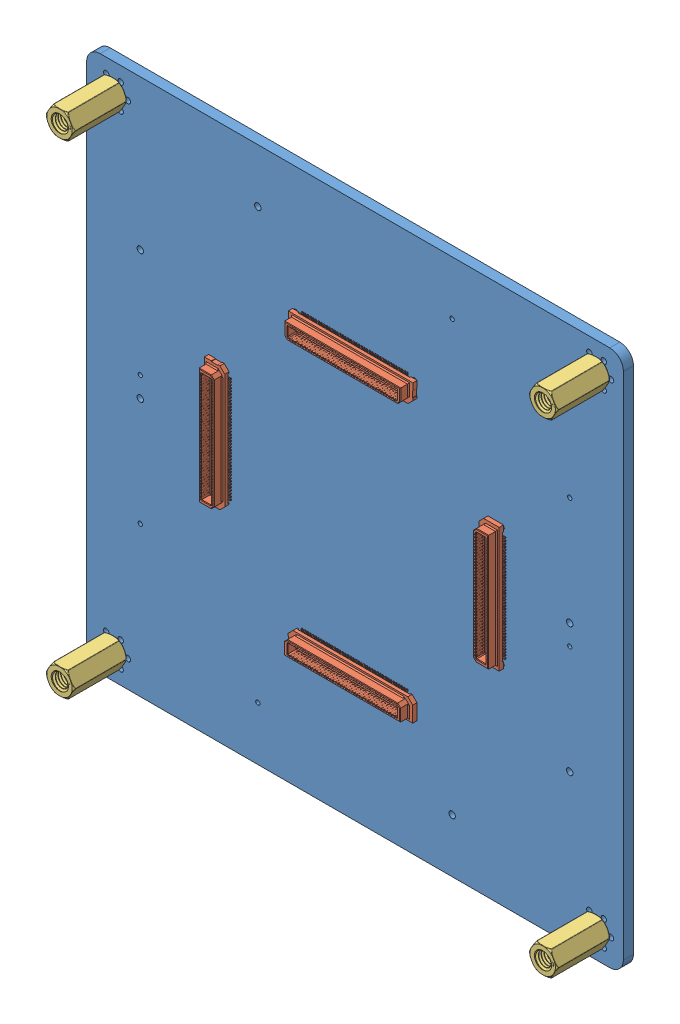
SolidWorks assembly fpgaboard, configuration 默认. Lengths in mm.
Overall size (100 100 11.96).
6 component instances, 3 part files, 0 mates.
Components (placement in the parent):
- fpgaboard_BOARD-1: fpgaboard_BOARD [默认] at origin size (100 100 1.87)
- AX7A200_AX7A200-1-1: AX7A200_AX7A200-1 [默认] at (96.901 64.516 1.8635) size (55.72 55.72 2.4)
- M3x10_N_铜柱大焊盘-1-1: M3x10_N_铜柱大焊盘-1 [默认] at (141.901 109.516 1.8635) size (5.4 5.21 10.1)
- M3x10_N_铜柱大焊盘-1-2: M3x10_N_铜柱大焊盘-1 [默认] at (141.901 19.516 1.8635) size (5.4 5.21 10.1)
- M3x10_N_铜柱大焊盘-1-3: M3x10_N_铜柱大焊盘-1 [默认] at (51.901 19.516 1.8635) size (5.4 5.21 10.1)
- M3x10_N_铜柱大焊盘-1-4: M3x10_N_铜柱大焊盘-1 [默认] at (51.901 109.516 1.8635) size (5.4 5.21 10.1)
